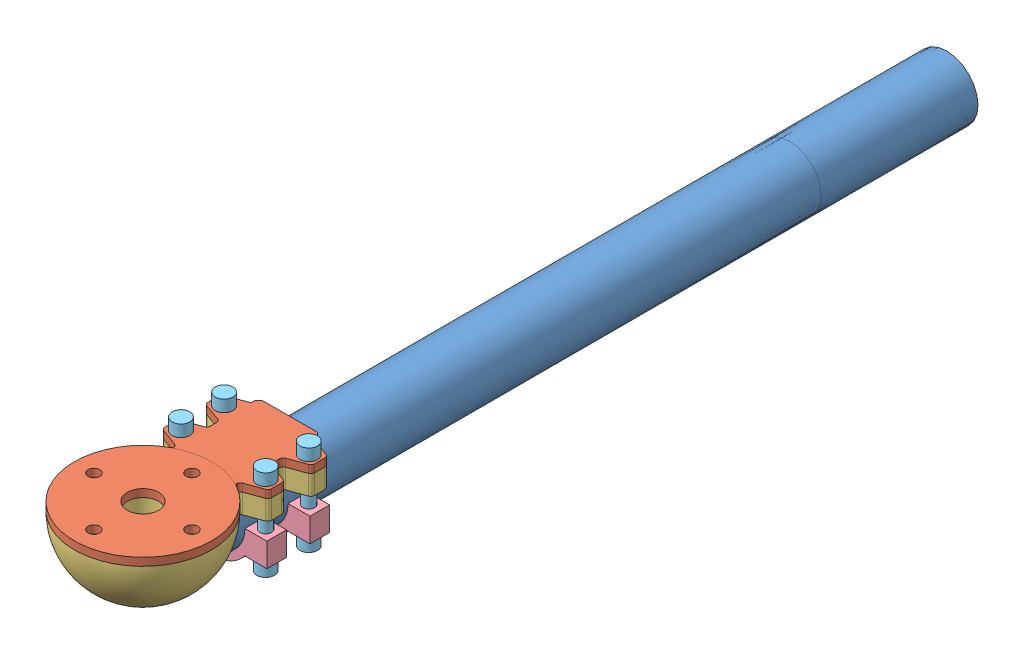
SolidWorks assembly mt-5, configuration Varsayılan. Lengths in mm.
Overall size (35 24 222.5).
9 component instances, 5 part files, 18 mates.
Components (placement in the parent):
- boru-1: boru [Varsayılan] at origin size (16 16 200)
- kf motor plakası-1: kf motor plakası [Varsayılan] at (0 9 205) x (-1 0 0) z (0 0 -1) size (35 2 55)
- motor desteği-1: motor desteği [Varsayılan] at (0 9 205) size (35 17.04 55)
- Lowerclamp-1: Lowerclamp [Default] at (0 0 171) size (27.2 10 5)
- Lowerclamp-2: Lowerclamp [Default] at (0 0 182) size (27.2 10 5)
- perçin-1: perçin [Varsayılan] at (10.8 -6.1 184.5) size (4.5 23.1 4.5)
- perçin-2: perçin [Varsayılan] at (10.8 -6.1 173.5) x (0.982082 0 -0.188455) z (0.188455 0 0.982082) size (4.5 23.1 4.5)
- perçin-3: perçin [Varsayılan] at (-10.8 -6.1 173.5) x (0.918365 0 -0.395734) z (0.395734 0 0.918365) size (4.5 23.1 4.5)
- perçin-4: perçin [Varsayılan] at (-10.8 -6.1 184.5) x (0.8 0 -0.6) z (0.6 0 0.8) size (4.5 23.1 4.5)
Mates (geometry in assembly coordinates):
- Concentric1: concentric aligned: circle of kf motor plakası-1; cylinder of motor desteği-1 through (0 -8.5 205) axis (0 1 0) radius 4
- Coincident2: coincident anti-aligned: plane of kf motor plakası-1 through (0 9 205) normal (0 -1 0); plane of motor desteği-1 through (0 9 205) normal (0 1 0)
- Coincident3: coincident anti-aligned: plane of kf motor plakası-1 through (0 9 205) normal (-1 0 0); plane of motor desteği-1 through (0 9 205) normal (1 0 0)
- Concentric2: concentric anti-aligned: cylinder of motor desteği-1 through (0 0 167.5) axis (0 0 1) radius 8; cylinder of boru-1 through (0 0 200) axis (0 0 -1) radius 8
- Coincident4: coincident anti-aligned: plane of motor desteği-1 through (0 0 200) normal (0 0 -1); plane of boru-1 through (0 0 200) normal (0 0 1)
- Concentric3: concentric aligned: cylinder of boru-1 through (0 0 200) axis (0 0 -1) radius 8; cylinder of Lowerclamp-1 through (0 0 176) axis (0 0 -1) radius 8
- Concentric4: concentric anti-aligned: cylinder of kf motor plakası-1 through (10.8 20.828 173.5) axis (0 -1 0) radius 1.5; cylinder of Lowerclamp-1 through (10.8 -10 173.5) axis (0 1 0) radius 1.5
- Concentric5: concentric aligned: cylinder of boru-1 through (0 0 200) axis (0 0 -1) radius 8; cylinder of Lowerclamp-2 through (0 0 187) axis (0 0 -1) radius 8
- Concentric6: concentric anti-aligned: cylinder of kf motor plakası-1 through (10.8 20.828 184.5) axis (0 -1 0) radius 1.5; cylinder of Lowerclamp-2 through (10.8 -10 184.5) axis (0 1 0) radius 1.5
- Coincident5: coincident aligned: plane of boru-1 through (0 0 0) normal (1 0 0); plane of motor desteği-1 through (0 9 205) normal (1 0 0)
- Concentric7: concentric aligned: cylinder of kf motor plakası-1 through (10.8 20.828 184.5) axis (0 -1 0) radius 1.5; cylinder of perçin-1 through (10.8 11 184.5) axis (0 -1 0) radius 1.5
- Coincident6: coincident anti-aligned: plane of kf motor plakası-1 through (0 11 205) normal (0 1 0); plane of perçin-1 through (10.8 11 184.5) normal (0 -1 0)
- Concentric8: concentric aligned: cylinder of kf motor plakası-1 through (10.8 20.828 173.5) axis (0 -1 0) radius 1.5; cylinder of perçin-2 through (10.8 11 173.5) axis (0 -1 0) radius 1.5
- Coincident7: coincident anti-aligned: plane of kf motor plakası-1 through (0 11 205) normal (0 1 0); plane of perçin-2 through (10.8 11 173.5) normal (0 -1 0)
- Coincident8: coincident anti-aligned: plane of kf motor plakası-1 through (0 11 205) normal (0 1 0); plane of perçin-3 through (-10.8 11 173.5) normal (0 -1 0)
- Concentric9: concentric aligned: cylinder of kf motor plakası-1 through (-10.8 20.828 173.5) axis (0 -1 0) radius 1.5; cylinder of perçin-3 through (-10.8 11 173.5) axis (0 -1 0) radius 1.5
- Coincident9: coincident anti-aligned: plane of kf motor plakası-1 through (0 11 205) normal (0 1 0); plane of perçin-4 through (-10.8 11 184.5) normal (0 -1 0)
- Concentric10: concentric aligned: cylinder of kf motor plakası-1 through (-10.8 20.828 184.5) axis (0 -1 0) radius 1.5; cylinder of perçin-4 through (-10.8 11 184.5) axis (0 -1 0) radius 1.5
